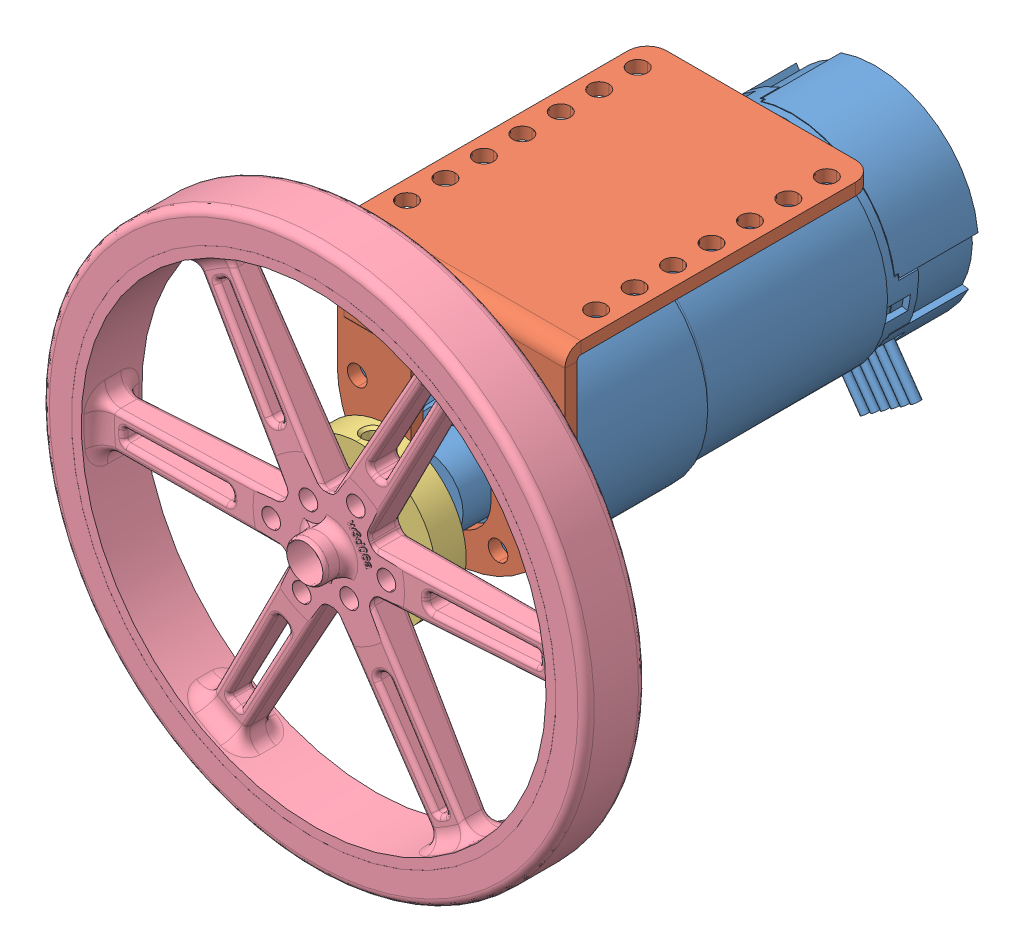
SolidWorks assembly Motor bracket hub and wheel 60, configuration Default. Lengths in mm.
Overall size (124.02 124.02 94.26).
4 component instances, 4 part files, 8 mates.
Components (placement in the parent):
- Motor-1: Motor [Default] at (-34.4414 -9.6533 18.8274) size (36.88 41.23 90.1)
- L bracket-1: L bracket [Default] at (-15.5164 -8.6533 32.9524) x (-1 0 0) z (0 0 1) size (37.59 39.6 51.2)
- Hub-1: Hub [Default] at (-14.5163 -16.6533 53.4524) x (-0.882948 0.469472 0) z (0 0 -1) size (25.4 25.4 9.2)
- Wheel-1: Wheel [Default] at (-14.5164 -16.6533 58.4524) x (0 0 -1) z (0.529919 -0.848048 0) size (11.46 90 90)
Mates (geometry in assembly coordinates):
- Coincident1: coincident: plane of Motor-1 through (-14.5164 -9.6533 38.7524) normal (0 0 1); plane of L bracket-1 through (-33.3124 9.1467 38.7524) normal (0 0 -1)
- Concentric1: concentric: circle of Motor-1; circle of L bracket-1
- Concentric2: concentric: circle of Motor-1; circle of L bracket-1
- Distance2: distance = 2 mm: plane of Hub-1 through (-14.5164 -16.6533 46.7524) normal (0 0 -1); plane of Motor-1 through (-14.5164 -9.6533 44.7524) normal (0 0 1)
- Concentric5: concentric: circle of Motor-1; circle of Hub-1
- Concentric6: concentric: circle of Motor-1; circle of Wheel-1
- Concentric7: concentric: circle of Hub-1; circle of Wheel-1
- Coincident5: coincident: plane of Hub-1 through (-14.5164 -16.6533 55.9524) normal (0 0 1); plane of Wheel-1 through (-25.117 -23.2773 55.9524) normal (0 0 -1)
